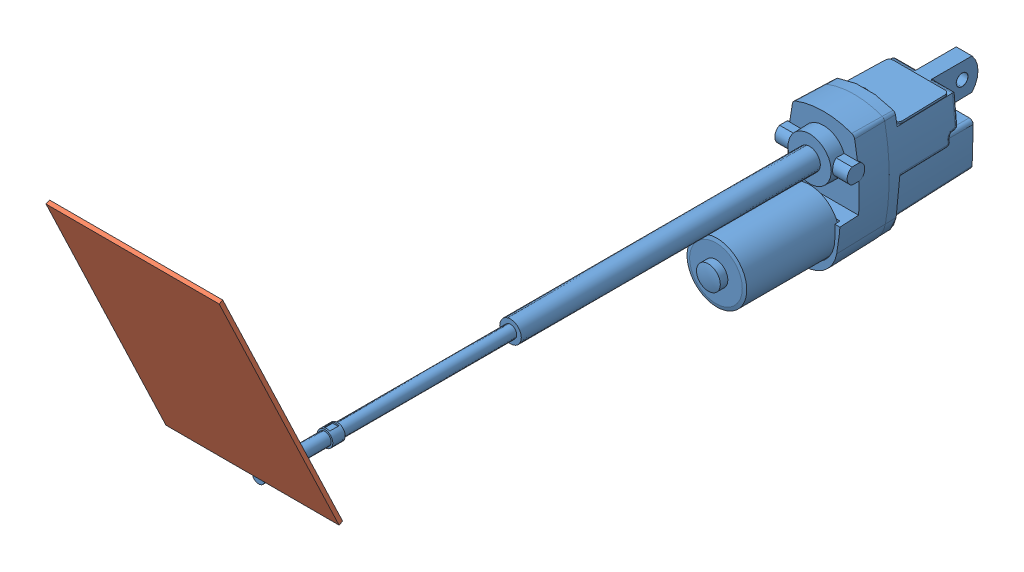
SolidWorks assembly Table adjustable123, configuration Default. Lengths in mm.
Overall size (279.4 562.58 1474.89).
2 component instances, 2 part files, 2 mates.
Components (placement in the parent):
- 6530K44_High-Force Electric Actuator-1: 6530K44_High-Force Electric Actuator [6530K44] at (-19.1688 36.2074 -301.1459) size (116.84 208.81 1147.98)
- Table adjustable part 1-1: Table adjustable part 1 [Default] at (-32.9864 81.7871 595.4751) x (0 0.788642 -0.614852) z (1 0 0) size (208.41 422.6 279.4)
Mates (geometry in assembly coordinates):
- Concentric12: concentric aligned: cylinder of 6530K44_High-Force Electric Actuator-1 through (-77.5888 36.2074 580.8691) axis (1 0 0) radius 3.4989; cylinder of Table adjustable part 1-1 through (-32.9864 36.2074 580.8691) axis (1 0 0) radius 3.4989
- Tangent3: tangent anti-aligned: cylinder of 6530K44_High-Force Electric Actuator-1 through (-19.1688 36.2074 587.8541) axis (0 0 -1) radius 9.9949; plane of Table adjustable part 1-1 through (-9.1739 59.8552 557.0165) normal (-1 0 0)
